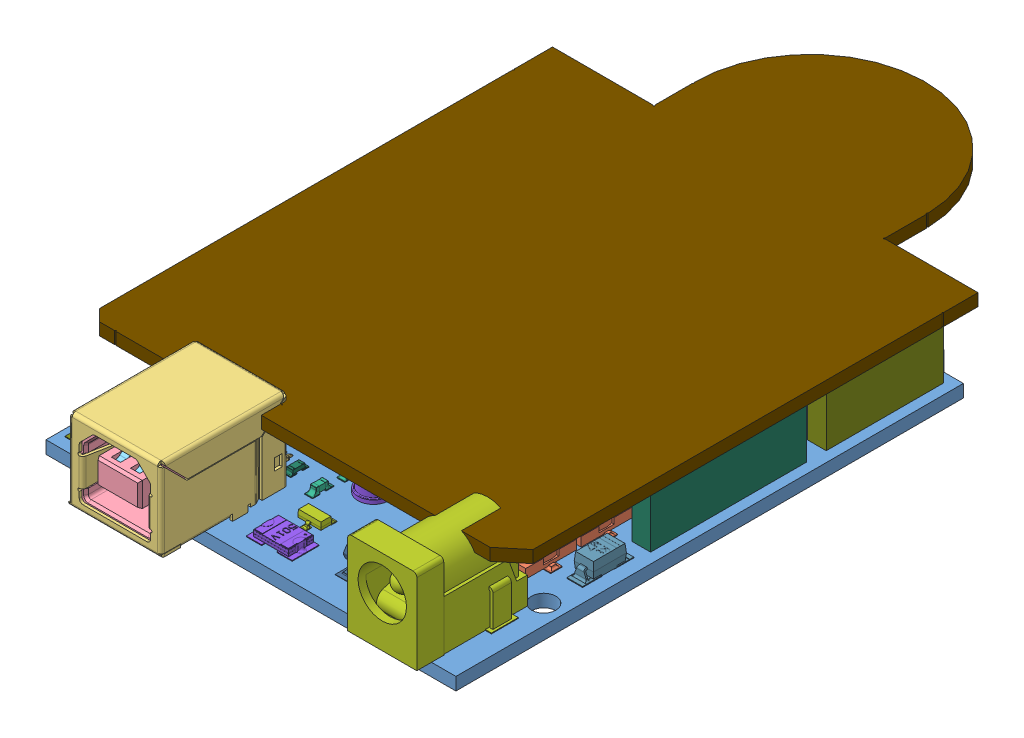
SolidWorks assembly arduino-assembly, configuration Default. Lengths in mm.
Overall size (55.37 15.25 93.83).
89 component instances, 36 part files, 0 mates.
Components (placement in the parent):
- arduino uno-1: arduino uno [Default] at (45.987 22.0292 102.4984) size (53.34 15.25 74.97)
  - unoboard blue-1: unoboard blue [Default] at origin size (53.34 1.65 68.58)
  - 47uf CAP Dcase-1: 47uf CAP Dcase [Default] at (-9.4141 0 -18.4991) x (0 0 -1) z (1 0 0) size (6.6 5.81 8)
  - USB type b-1: USB type b [Default] at (-38.02 0.43 6.35) size (14.34 15.2 16.54)
    - USB SHELL-1: USB SHELL [Default] at origin size (14.34 15.2 16.54)
    - USB core-1: USB core [Default] at origin size (11.3 10.68 15.75)
    - usb top contact-1: usb top contact [Default] at (1.25 6.09 -0.38) size (1 9.67 13.76)
    - usb btm contact-1: usb btm contact [Default] at (1.25 4.41 -0.38) size (1 6.84 11.76)
    - usb btm contact-2: usb btm contact [Default] at (-1.25 4.41 -0.38) size (1 6.84 11.76)
    - usb top contact-2: usb top contact [Default] at (-1.25 6.09 -0.38) size (1 9.67 13.76)
  - power jack-1: power jack [Default] at (-7.675 0 1.905) size (11.2 15.2 15.9)
  - 47uf CAP Dcase-2: 47uf CAP Dcase [Default] at (-9.4141 0 -25.7132) x (0 0 -1) z (1 0 0) size (6.6 5.81 8)
  - crystal-1: crystal [Default] at (-26.162 0 -18.923) x (1 0 0) z (0 0 -1) size (4 5 11)
  - 2pin_header__02-1: 2pin_header__02 [Default] at (-46.23 0 -15.75) size (5 11.75 2.54)
  - nano - reg-1: nano - reg [Default] at (-17.399 0 -7.747) size (6.5 1.69 8.3)
  - led-1: led [Default] at (-34.29 0 -27.94) x (0 0 1) z (-1 0 0) size (4 0.86 1.35)
  - 2pin_header__02-2: 2pin_header__02 [Default] at (-30.43 0 -64.91) x (0 0 1) z (-1 0 0) size (5 11.75 2.54)
  - dip28-1: dip28 [Default] at (-16.383 1.5 -46.355) x (0 0 -1) z (1 0 0) size (35.48 7.37 10.1)
    - dip28-1: dip28 [Default] at origin size (35.48 2.8 10.1)
    - dip socket pin-1: dip socket pin [Default] at (16.51 2.8 -3.81) size (1.7 7.37 1.7)
    - dip socket pin-2: dip socket pin [Default] at (16.51 2.8 3.81) size (1.7 7.37 1.7)
    - dip socket pin-3: dip socket pin [Default] at (13.97 2.8 -3.81) size (1.7 7.37 1.7)
    - dip socket pin-4: dip socket pin [Default] at (13.97 2.8 3.81) size (1.7 7.37 1.7)
    - dip socket pin-5: dip socket pin [Default] at (11.43 2.8 -3.81) size (1.7 7.37 1.7)
    - dip socket pin-6: dip socket pin [Default] at (11.43 2.8 3.81) size (1.7 7.37 1.7)
    - dip socket pin-7: dip socket pin [Default] at (8.89 2.8 -3.81) size (1.7 7.37 1.7)
    - dip socket pin-8: dip socket pin [Default] at (8.89 2.8 3.81) size (1.7 7.37 1.7)
    - dip socket pin-9: dip socket pin [Default] at (6.35 2.8 -3.81) size (1.7 7.37 1.7)
    - dip socket pin-10: dip socket pin [Default] at (6.35 2.8 3.81) size (1.7 7.37 1.7)
    - dip socket pin-11: dip socket pin [Default] at (3.81 2.8 -3.81) size (1.7 7.37 1.7)
    - dip socket pin-12: dip socket pin [Default] at (3.81 2.8 3.81) size (1.7 7.37 1.7)
    - dip socket pin-13: dip socket pin [Default] at (1.27 2.8 -3.81) size (1.7 7.37 1.7)
    - dip socket pin-14: dip socket pin [Default] at (1.27 2.8 3.81) size (1.7 7.37 1.7)
    - dip socket pin-15: dip socket pin [Default] at (-1.27 2.8 -3.81) size (1.7 7.37 1.7)
    - dip socket pin-16: dip socket pin [Default] at (-1.27 2.8 3.81) size (1.7 7.37 1.7)
    - dip socket pin-17: dip socket pin [Default] at (-3.81 2.8 -3.81) size (1.7 7.37 1.7)
    - dip socket pin-18: dip socket pin [Default] at (-3.81 2.8 3.81) size (1.7 7.37 1.7)
    - dip socket pin-19: dip socket pin [Default] at (-6.35 2.8 -3.81) size (1.7 7.37 1.7)
    - dip socket pin-20: dip socket pin [Default] at (-6.35 2.8 3.81) size (1.7 7.37 1.7)
    - dip socket pin-21: dip socket pin [Default] at (-8.89 2.8 -3.81) size (1.7 7.37 1.7)
    - dip socket pin-22: dip socket pin [Default] at (-8.89 2.8 3.81) size (1.7 7.37 1.7)
    - dip socket pin-23: dip socket pin [Default] at (-11.43 2.8 -3.81) size (1.7 7.37 1.7)
    - dip socket pin-24: dip socket pin [Default] at (-11.43 2.8 3.81) size (1.7 7.37 1.7)
    - dip socket pin-25: dip socket pin [Default] at (-13.97 2.8 -3.81) size (1.7 7.37 1.7)
    - dip socket pin-26: dip socket pin [Default] at (-13.97 2.8 3.81) size (1.7 7.37 1.7)
    - dip socket pin-27: dip socket pin [Default] at (-16.51 2.8 -3.81) size (1.7 7.37 1.7)
    - dip socket pin-28: dip socket pin [Default] at (-16.51 2.8 3.81) size (1.7 7.37 1.7)
  - 2pin_header__02-3: 2pin_header__02 [Default] at (-27.89 0 -64.91) x (0 0 1) z (-1 0 0) size (5 11.75 2.54)
  - 2pin_header__02-4: 2pin_header__02 [Default] at (-25.35 0 -64.91) x (0 0 1) z (-1 0 0) size (5 11.75 2.54)
  - 2pin_header__02-5: 2pin_header__02 [Default] at (-46.23 0 -18.29) size (5 11.75 2.54)
  - 2pin_header__02-6: 2pin_header__02 [Default] at (-46.23 0 -20.83) size (5 11.75 2.54)
  - atmega16u2-1: atmega16u2 [Default] at (-34.671 0.06 -20) x (1 0 0) z (0 0 -1) size (5.5 1.01 5.5)
  - led-2: led [Default] at (-36.83 0 -27.94) x (0 0 1) z (-1 0 0) size (4 0.86 1.35)
  - led-3: led [Default] at (-42.037 0 -27.94) x (0 0 1) z (-1 0 0) size (4 0.86 1.35)
  - led-4: led [Default] at (-36.576 0 -58.42) x (0 0 1) z (-1 0 0) size (4 0.86 1.35)
  - 8 PORT HEADER-3: 8 PORT HEADER [Default] at (-50.8 0 -45.72) x (0 0 -1) z (1 0 0) size (20.32 10.51 2.41)
  - 8 PORT HEADER-4: 8 PORT HEADER [Default] at (-2.54 0 -27.94) x (0 0 -1) z (1 0 0) size (20.32 10.51 2.41)
  - 6 PORT HEADER-3: 6 PORT HEADER [Default] at (-2.54 0 -50.8) x (0 0 -1) z (1 0 0) size (15.24 10.51 2.41)
  - 10 PORT HEADER-1: 10 PORT HEADER [Default] at (-50.8 0 -18.796) x (0 0 -1) z (1 0 0) size (25.4 10.51 2.41)
  - ATMEL328P-1: ATMEL328P [Default] at (-16.383 4.3 -46.355) x (0 0 -1) z (1 0 0) size (35 7.27 7.87)
  - 102 RESISTOR PACK-1: 102 RESISTOR PACK [Default] at (-33.782 0 -58.42) size (3.2 0.46 3)
  - 102 RESISTOR PACK-2: 102 RESISTOR PACK [Default] at (-39.37 0 -27.94) size (3.2 0.46 3)
  - 103 RESISTOR PACK-3: 103 RESISTOR PACK [Default] at (-23.876 0 -27.94) size (3.2 0.46 3)
  - 220 RESISTOR PACK-1: 220 RESISTOR PACK [Default] at (-36.83 0 -12.827) size (3.2 0.46 3)
  - 16mhz crystal - measured-1: 16mhz crystal - measured [Default] at (-24.892 0 -41.275) x (0 0 -1) z (1 0 0) size (3.4 0.8 2)
  - PADS001-1: PADS001 [Default] at (-39.878 0.1 -18.288) x (-1 0 0) z (0 0 1) size (4.54 0.1 4.54)
  - 603 cap on pad-1: 603 cap on pad [Default] at (-44.45 0 -27.94) x (0 0 -1) z (1 0 0) size (2.76 0.9 1.12)
  - ssot3-1: ssot3 [Default] at (-26.5 0 -8.128) x (-1 0 0) z (0 0 -1) size (3 1.13 3.09)
  - mf-msmf050-2-1: mf-msmf050-2 [Default] at (-26.5 0 -4.064) size (5.77 1.02 3.72)
  - 603 cap on pad-2: 603 cap on pad [Default] at (-29.845 0 -27.94) x (0 0 -1) z (1 0 0) size (2.76 0.9 1.12)
  - 603 cap on pad-3: 603 cap on pad [Default] at (-31.496 0 -27.94) x (0 0 -1) z (1 0 0) size (2.76 0.9 1.12)
  - lmv358-1: lmv358 [Default] at (-15.24 0 -21.971) x (0 0 -1) z (1 0 0) size (3.7 1.4 2.9)
  - 603 cap on pad-4: 603 cap on pad [Default] at (-15.24 0 -18.415) size (2.76 0.9 1.12)
  - 603 cap on pad-5: 603 cap on pad [Default] at (-29.845 0 -12.065) x (0 0 1) z (-1 0 0) size (2.76 0.9 1.12)
  - 603 cap on pad-6: 603 cap on pad [Default] at (-29.591 0 -22.352) x (0 0 1) z (-1 0 0) size (2.76 0.9 1.12)
  - 603 cap on pad-7: 603 cap on pad [Default] at (-29.591 0 -16.002) x (0 0 1) z (-1 0 0) size (2.76 0.9 1.12)
  - 603 cap on pad-8: 603 cap on pad [Default] at (-41.91 0 -12.7) x (0 0 1) z (-1 0 0) size (2.76 0.9 1.12)
  - lp2985dgkr-1: lp2985dgkr [Default] at (-20.32 0 -19.05) x (0 0 -1) z (1 0 0) size (5.85 1.1 3)
  - cd1206 diode-1: cd1206 diode [Default] at (-27.94 0 -59.436) x (0 0 -1) z (1 0 0) size (2.07 0.96 5)
  - cd1206 diode-2: cd1206 diode [Default] at (-46.228 0 -13.081) x (0 0 1) z (-1 0 0) size (2.07 0.96 5)
  - 603 resistor-1: 603 resistor [Default] at (-29.591 0 -19.05) x (0 0 1) z (-1 0 0) size (2.36 0.61 1.03)
  - blm21-1: blm21 [Default] at (-45.085 0 -7.62) x (0 0 -1) z (1 0 0) size (2.76 0.95 1.32)
  - m7 diode-1: m7 diode [Default] at (-2.794 0 -21.59) x (0 0 -1) z (1 0 0) size (6.66 2.35 2.5)
  - MLC0603-1: MLC0603 [Default] at (-33.655 0 -12.827) x (0 0 -1) z (1 0 0) size (2.36 0.6 1.03)
  - MLC0603-2: MLC0603 [Default] at (-39.37 0 -12.827) x (0 0 -1) z (1 0 0) size (2.36 0.6 1.03)
  - RESET BUTTON-1: RESET BUTTON [Default] at (-49.403 0 -6.35) size (6.2 3.1 9.6)
    - RESET CORE-1: RESET CORE [Default] at (0 0.1 0) x (-1 0 0) z (0 0 -1) size (6.2 3.1 9.6)
    - RESET-1: RESET [Default] at (0 0.1 0) x (0 0 1) z (-1 0 0) size (7.3 2 6.2)
- PCB-1: PCB [Default] at origin size (55.37 1.59 80.77)
